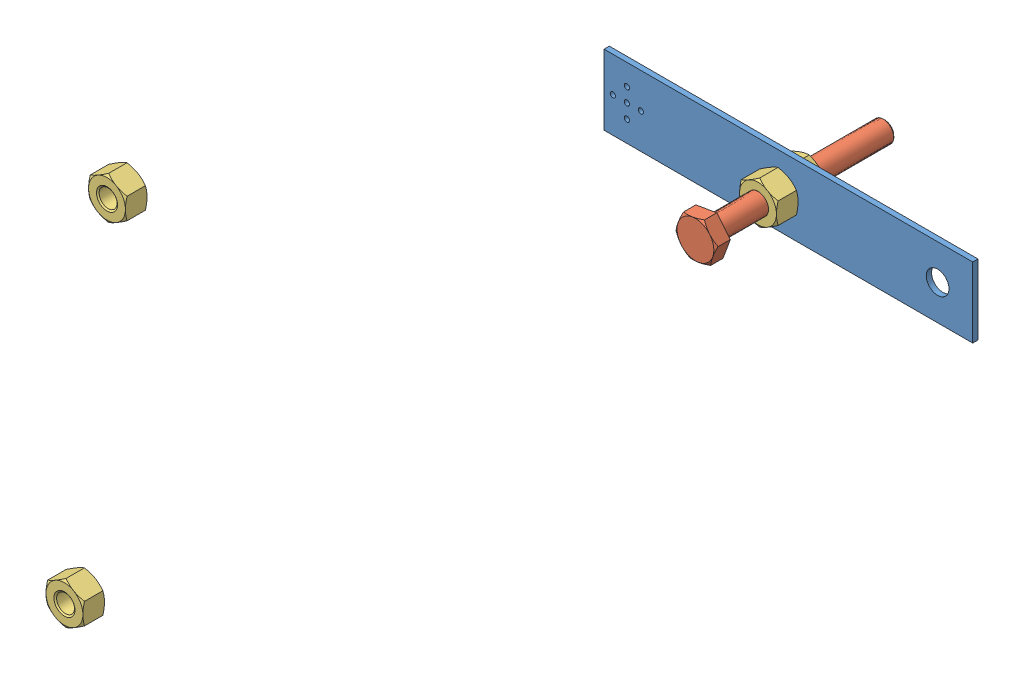
SolidWorks assembly Assem1, configuration Default. Lengths in mm.
Overall size (210 238.18 467.38).
6 component instances, 3 part files, 9 mates.
Components (placement in the parent):
- ServoRod-1: ServoRod [Default] at (10 20 0) size (210 40 3)
- heavy hex bolt_am-1: heavy hex bolt_am [B18.2.3.6M - Heavy hex bolt M12 x 1.75 x 100 --100S] at (100 20 50.95) x (0 0 -1) z (-0.769578 -0.638552 0) size (107.95 24.25 21)
- hex nut heavy_am-1: hex nut heavy_am [B18.2.4.6M - Heavy hex nut,  M12 x 1.75 --D-N] at (100 20 410.3814) size (21 24.25 12.3)
- hex nut heavy_am-2: hex nut heavy_am [B18.2.4.6M - Heavy hex nut,  M12 x 1.75 --D-N] at (100 20 15.3) size (21 24.25 12.3)
- hex nut heavy_am-3: hex nut heavy_am [B18.2.4.6M - Heavy hex nut,  M12 x 1.75 --D-N] at (118.335 226.0576 404.4724) size (21 24.25 12.3)
- hex nut heavy_am-4: hex nut heavy_am [B18.2.4.6M - Heavy hex nut,  M12 x 1.75 --D-N] at (100 20 -12.3) x (-0.978886 0.204405 0) z (0 0 -1) size (21 24.25 12.3)
Mates (geometry in assembly coordinates):
- Parallel1: parallel anti-aligned: plane of ServoRod-1 through (10 20 3) normal (0 0 1); plane of heavy hex bolt_am-1 through (107.742 10.6694 43) normal (0 0 -1)
- Concentric2: concentric anti-aligned: cylinder of heavy hex bolt_am-1 through (100 20 50.95) axis (0 0 1) radius 6; cylinder of hex nut heavy_am-4 through (100 20 0) axis (0 0 -1) radius 5.1
- Concentric3: concentric aligned: cylinder of heavy hex bolt_am-1 through (100 20 50.95) axis (0 0 1) radius 6; cylinder of hex nut heavy_am-1 through (100 20 398.0814) axis (0 0 1) radius 5.1
- Coincident5: coordinate: point of ServoRod-1; point of assembly
- Concentric4: concentric aligned: cylinder of ServoRod-1 through (100 20 3) axis (0 0 1) radius 6.5; cylinder of heavy hex bolt_am-1 through (100 20 50.95) axis (0 0 1) radius 6
- Distance2: distance = 40 mm anti-aligned: plane of heavy hex bolt_am-1 through (107.742 10.6694 43) normal (0 0 -1); plane of ServoRod-1 through (10 20 3) normal (0 0 1)
- Coincident7: coincident anti-aligned: plane of ServoRod-1 through (10 20 0) normal (0 0 -1); plane of hex nut heavy_am-4 through (120.5566 15.7075 0) normal (0 0 1)
- Coincident8: coincident anti-aligned: plane of ServoRod-1 through (10 20 3) normal (0 0 1); plane of hex nut heavy_am-2 through (79 20 3) normal (0 0 -1)
- Concentric5: concentric aligned: cylinder of ServoRod-1 through (100 20 3) axis (0 0 1) radius 6.5; cylinder of hex nut heavy_am-2 through (100 20 3) axis (0 0 1) radius 5.1
